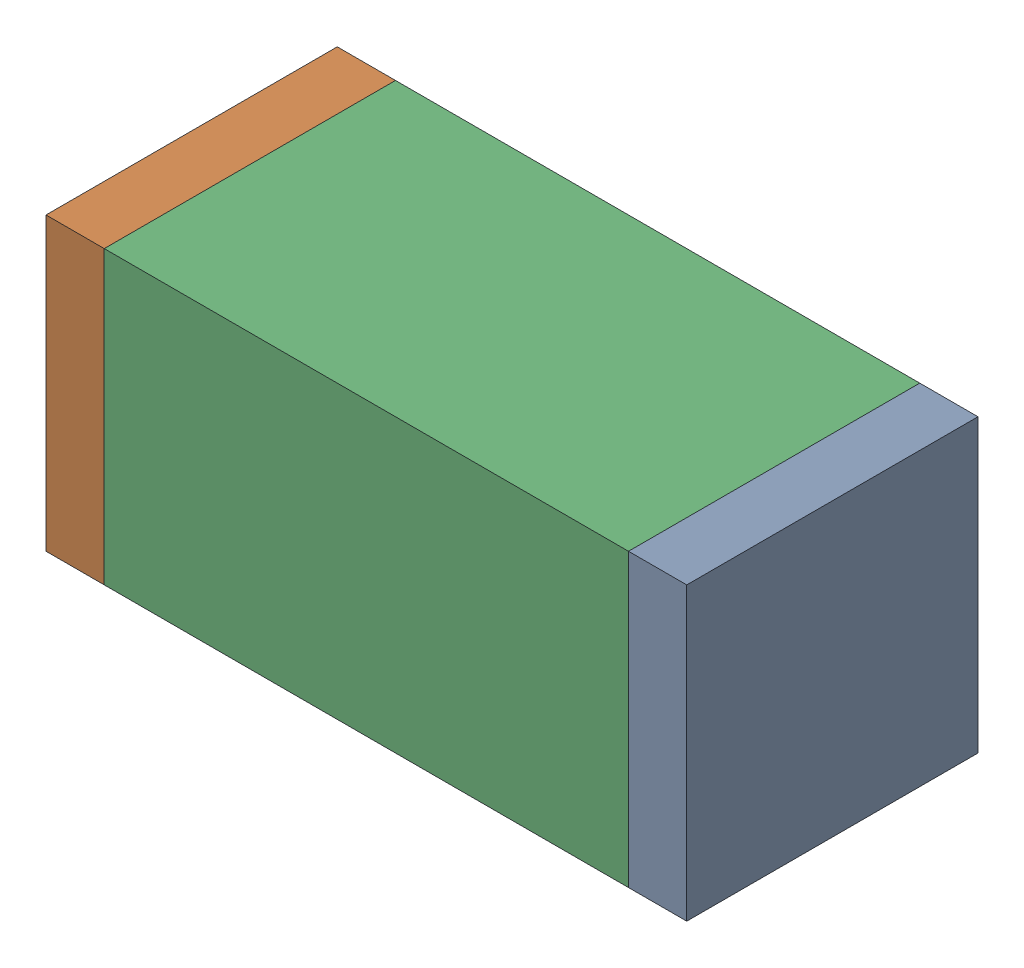
SolidWorks assembly C84, configuration Default. Lengths in mm.
Overall size (1.1 0.5 0.5).
6 component instances, 2 part files, 0 mates.
Components (placement in the parent):
- 810156080-1: 810156080 [Default] at (119.9 62.45 0) size (0.1 0.5 0.5)
  - Extruded_5-1: Extruded_5 [Default] at origin size (0.1 0.5 0.5)
- 810156080-2: 810156080 [Default] at (118.9 62.45 0) size (0.1 0.5 0.5)
  - Extruded_5-1: Extruded_5 [Default] at origin size (0.1 0.5 0.5)
- 836749680-1: 836749680 [Default] at (119.4 62.45 0) size (0.9 0.5 0.5)
  - Extruded_4-1: Extruded_4 [Default] at origin size (0.9 0.5 0.5)
